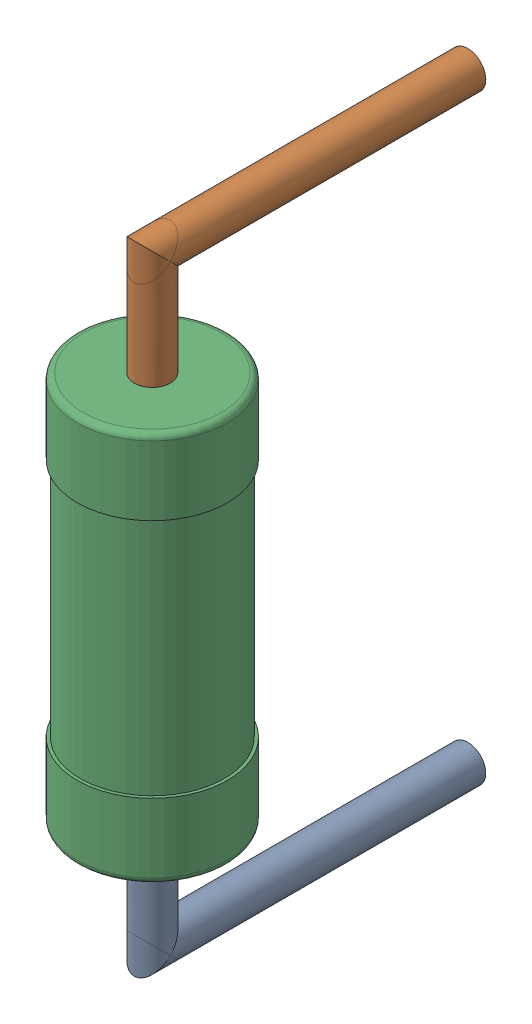
SolidWorks assembly R4.step, configuration Default. Lengths in mm.
Overall size (2.5 10.6 6.5).
3 component instances, 3 part files, 0 mates.
Components (placement in the parent):
- Res_Vishay_BC_Components_MRS25000C1101FCT00_eec.step-1: Res_Vishay_BC_Components_MRS25000C1101FCT00_eec.step [Default] at (18.161 21.463 0) x (0 1 0) z (0 0 1) size (2.05 0.6 5.55)
- Res_Vishay_BC_Components_MRS25000C1101FCT00_eec-2.step-1: Res_Vishay_BC_Components_MRS25000C1101FCT00_eec-2.step [Default] at (18.161 21.463 0) x (0 1 0) z (0 0 1) size (2.05 0.6 5.55)
- Res_Vishay_BC_Components_MRS25000C1101FCT00_eec-3.step-1: Res_Vishay_BC_Components_MRS25000C1101FCT00_eec-3.step [Default] at (18.161 21.463 0) x (0 1 0) z (0 0 1) size (6.5 2.5 2.5)
